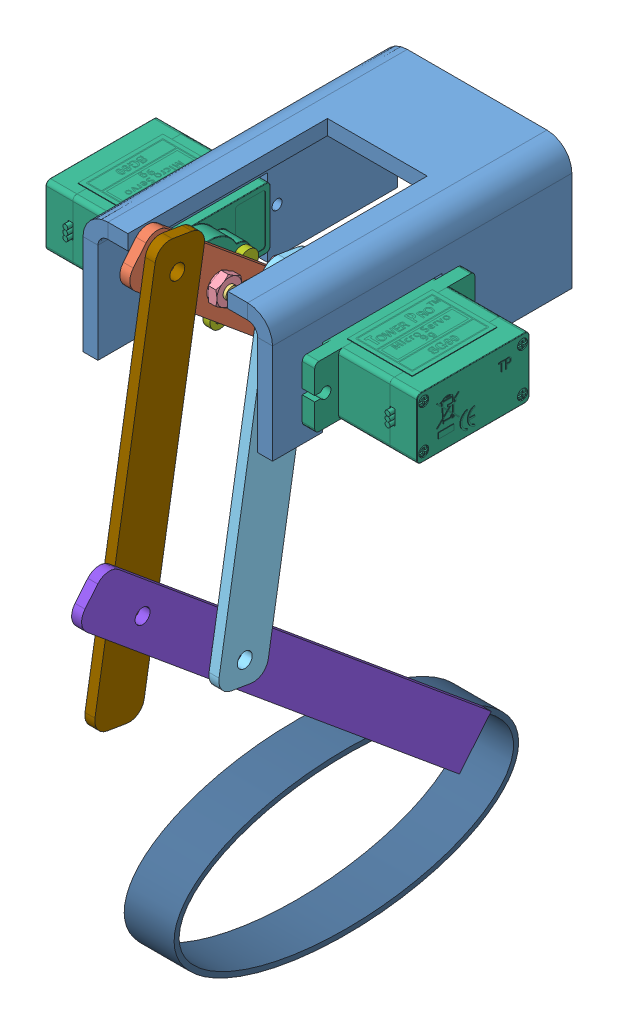
SolidWorks assembly 4 bar solution assembly, configuration Default. Lengths in mm.
Overall size (74.6 140.44 90.84).
18 component instances, 10 part files, 59 mates.
Components (placement in the parent):
- casing for the 4 bar linkage-1: casing for the 4 bar linkage [Default] at (-5.3742 30.1241 -30.819) size (38 25 60)
- arm for servo1-1: arm for servo1 [Default] at (-14.4242 18.8349 7.0956) x (0 -0.638517 -0.769608) z (0 -0.769608 0.638517) size (40 2 10)
- pan head cross recess screw_bsi-2: pan head cross recess screw_bsi [BS EN ISO 7045 - M2.5 x 6 - Z - 6N] at (-17.9242 18.3433 6.5031) x (1 0 0) z (0 -0.535382 -0.84461) size (8.05 5 5)
- pan head cross recess screw_bsi-3: pan head cross recess screw_bsi [BS EN ISO 7045 - M2.5 x 6 - Z - 6N] at (-17.9242 10.1064 -3.4249) x (1 0 0) z (0 -0.826379 -0.563115) size (8.05 5 5)
- hex nut style 1 gradeab_bsi-5: hex nut style 1 gradeab_bsi [BS EN 24032 - M2.5 - W - N] at (-10.4242 10.1064 -3.4249) x (0 -0.306449 -0.951887) z (1 0 0) size (5 5.77 2)
- hex nut style 1 gradeab_bsi-6: hex nut style 1 gradeab_bsi [BS EN 24032 - M2.5 - W - N] at (-10.4242 18.3433 6.5031) x (0 0 -1) z (1 0 0) size (5 5.77 2)
- arm for servo2-1: arm for servo2 [Default] at (-3.3242 -9.8625 5.5192) x (0 0.986622 -0.163025) z (0 0.163025 0.986622) size (70 2 10)
- pan head cross recess screw_bsi-4: pan head cross recess screw_bsi [BS EN ISO 7045 - M2.5 x 6 - Z - 6N] at (0.1758 20.5885 0.4876) x (-1 0 0) z (0 -0.368719 0.929541) size (8.05 5 5)
- pan head cross recess screw_bsi-5: pan head cross recess screw_bsi [BS EN ISO 7045 - M2.5 x 6 - Z - 6N] at (0.1758 7.8611 2.5906) x (-1 0 0) z (0 -0.591563 0.806259) size (8.05 5 5)
- hex nut style 1 gradeab_bsi-8: hex nut style 1 gradeab_bsi [BS EN 24032 - M2.5 - W - N] at (-7.3242 20.5885 0.4876) x (0 -0.76274 -0.646705) z (-1 0 0) size (5 5.77 2)
- hex nut style 1 gradeab_bsi-10: hex nut style 1 gradeab_bsi [BS EN 24032 - M2.5 - W - N] at (-7.3242 7.8611 2.5906) x (0 -0.76274 -0.646705) z (-1 0 0) size (5 5.77 2)
- SG90 - Micro Servo 9g - Tower Pro.1-1: SG90 - Micro Servo 9g - Tower Pro.1 [Peça] at (17.7758 14.2248 -3.6109) x (0 0 -1) z (0 1 0) size (32.1 29.95 12.4)
- SG90 - Micro Servo 9g - Tower Pro.4-1: SG90 - Micro Servo 9g - Tower Pro.4 [Peça] at (-3.3242 14.2248 1.5391) x (0 0.163025 0.986622) z (0 -0.986622 0.163025) size (13 3.8 16.7)
- SG90 - Micro Servo 9g - Tower Pro.1-2: SG90 - Micro Servo 9g - Tower Pro.1 [Peça] at (-35.5242 14.2248 -3.6109) x (0 0 -1) z (0 -1 0) size (32.1 29.95 12.4)
- SG90 - Micro Servo 9g - Tower Pro.4-2: SG90 - Micro Servo 9g - Tower Pro.4 [Peça] at (-14.4242 14.2248 1.5391) x (0 -0.769608 0.638517) z (0 0.638517 0.769608) size (13 3.8 16.7)
- arm for servo3-1: arm for servo3 [Default] at (-10.4242 -50.6831 -2.3235) x (0 0.638517 0.769608) z (0 0.769608 -0.638517) size (100 2 10)
- arm for servo4-1: arm for servo4 [Default] at (-10.4242 -6.55 22.4741) x (0 0.986622 -0.163025) z (0 0.163025 0.986622) size (80 2 10)
- path-1: path [Default] at (-10.4242 -88.8646 -16.9534) x (0 0 1) z (-1 0 0) size (69.07 32.24 10)
Mates (geometry in assembly coordinates):
- Coincident3: coincident: plane of casing for the 4 bar linkage-1 through (-27.8742 30.1241 -30.819) normal (-1 0 0); plane of ? through (-27.8742 19.4748 -34.3465) normal (1 0 0)
- Concentric1: concentric: circle of casing for the 4 bar linkage-1; circle of ?
- Coincident5: coincident: plane of casing for the 4 bar linkage-1 through (10.1258 30.1241 -30.819) normal (1 0 0); plane of ? through (10.1258 8.9748 -34.3465) normal (-1 0 0)
- Concentric4: concentric: circle of casing for the 4 bar linkage-1; circle of ?
- Concentric5: concentric: circle of casing for the 4 bar linkage-1; circle of ?
- Concentric6: concentric: circle of casing for the 4 bar linkage-1; circle of ?
- Concentric9: concentric: cylinder of ? through (-14.4242 16.4911 -18.2578) axis (1 0 0) radius 1.25; cylinder of pan head cross recess screw_bsi-2 through (-43.3242 16.4911 -18.2578) axis (-1 0 0) radius 2.5
- Coincident7: coincident: plane of ? through (-15.8242 14.2248 -24.2965) normal (-1 0 0); plane of pan head cross recess screw_bsi-2 through (-15.8242 16.0183 -17.1006) normal (1 0 0)
- Concentric10: concentric: cylinder of ? through (22.4036 20.7247 -24.2548) axis (1 0 0) radius 1.25; cylinder of pan head cross recess screw_bsi-3 through (-40.5964 20.7247 -24.2548) axis (-1 0 0) radius 2.5
- Coincident8: coincident: plane of ? through (-13.0964 20.2474 -23.0996) normal (-1 0 0); plane of pan head cross recess screw_bsi-3 through (-13.0964 21.9747 -24.2548) normal (1 0 0)
- Concentric11: concentric: cylinder of ? through (-14.4242 11.9585 -30.3352) axis (1 0 0) radius 1.25; cylinder of pan head cross recess screw_bsi-3 through (-43.3242 11.9585 -30.3352) axis (-1 0 0) radius 1.25
- Concentric16: concentric: cylinder of arm for servo1-1 through (-15.4242 7.7753 1.6192) axis (1 0 0) radius 1.3; cylinder of pan head cross recess screw_bsi-3 through (-43.3242 7.7753 1.6192) axis (-1 0 0) radius 1.25
- Concentric19: concentric: cylinder of arm for servo1-1 through (-15.4242 20.6743 1.459) axis (1 0 0) radius 1.3; cylinder of pan head cross recess screw_bsi-2 through (-43.3242 20.6743 1.459) axis (-1 0 0) radius 1.25
- Concentric20: concentric: cylinder of pan head cross recess screw_bsi-2 through (-40.8242 7.7748 -24.2965) axis (-1 0 0) radius 1.25; cylinder of ? through (19.4695 7.7748 -24.2965) axis (-1 0 0) radius 1.25
- Concentric21: concentric: cylinder of pan head cross recess screw_bsi-3 through (-40.8242 20.6748 -24.2965) axis (-1 0 0) radius 1.25; cylinder of ? through (19.1734 20.6748 -24.2965) axis (-1 0 0) radius 1.25
- Coincident91: coincident: plane of ? through (-15.8242 14.2248 -24.2965) normal (-1 0 0); plane of pan head cross recess screw_bsi-3 through (-15.8242 12.1731 -29.1038) normal (1 0 0)
- Coincident101: coincident: plane of ? through (-14.4242 14.2248 -24.2965) normal (1 0 0); plane of arm for servo1-1 through (-14.4242 23.4712 0.3412) normal (-1 0 0)
- Concentric23: concentric: cylinder of arm for servo1-1 through (-11.9242 7.7748 -24.2965) axis (1 0 0) radius 1.3; cylinder of ? through (-28.3617 7.7748 -24.2965) axis (1 0 0) radius 1.25
- Coincident11: coincident: plane of pan head cross recess screw_bsi-2 through (-5.3242 7.302 -23.1394) normal (1 0 0); plane of ? through (-5.3242 6.7113 -26.9802) normal (-1 0 0)
- Concentric24: concentric: cylinder of pan head cross recess screw_bsi-3 through (-43.3242 7.7753 1.6192) axis (-1 0 0) radius 1.25; cylinder of hex nut style 1 gradeab_bsi-5 through (-35.4617 7.7753 1.6192) axis (1 0 0) radius 1.25
- Coincident12: coincident: plane of arm for servo1-1 through (-12.4242 21.4442 1.4494) normal (1 0 0); plane of hex nut style 1 gradeab_bsi-5 through (-12.4242 10.5232 0.7346) normal (-1 0 0)
- Concentric251: concentric: cylinder of arm for servo1-1 through (-15.4242 20.6743 1.459) axis (1 0 0) radius 1.3; cylinder of hex nut style 1 gradeab_bsi-6 through (-35.4617 20.6743 1.459) axis (1 0 0) radius 1.25
- Coincident151: coincident: plane of arm for servo1-1 through (-12.4242 21.4442 1.4494) normal (1 0 0); plane of hex nut style 1 gradeab_bsi-6 through (-12.4242 23.5611 1.459) normal (-1 0 0)
- Concentric271: concentric: cylinder of ? through (-3.3242 16.4911 -30.3352) axis (-1 0 0) radius 1.25; cylinder of pan head cross recess screw_bsi-5 through (25.5758 16.4911 -30.3352) axis (1 0 0) radius 1.25
- Coincident171: coincident: plane of ? through (-1.9242 14.2248 -24.2965) normal (1 0 0); plane of pan head cross recess screw_bsi-5 through (-1.9242 15.435 -31.0038) normal (-1 0 0)
- Concentric281: concentric: cylinder of arm for servo2-1 through (-2.3242 8.0743 -0.4033) axis (-1 0 0) radius 1.3; cylinder of pan head cross recess screw_bsi-5 through (25.5758 8.0743 -0.4033) axis (1 0 0) radius 1.25
- Concentric301: concentric: cylinder of ? through (-3.3242 11.9585 -18.2578) axis (-1 0 0) radius 1.25; cylinder of pan head cross recess screw_bsi-4 through (25.6839 11.9585 -18.2578) axis (1 0 0) radius 1.25
- Concentric341: concentric: cylinder of arm for servo2-1 through (-6.3036 19.9092 -22.2965) axis (1 0 0) radius 3; cylinder of ? through (-30.2948 21.3681 -19.6751) axis (1 0 0) radius 1.25
- Coincident201: coincident: plane of arm for servo2-1 through (-6.3036 -12.0908 -24.2965) normal (-1 0 0); plane of ? through (-7.2573 24.193 -20.2695) normal (-1 0 0)
- Concentric351: concentric: cylinder of arm for servo2-1 through (-2.3242 20.3754 3.4816) axis (-1 0 0) radius 1.3; cylinder of hex nut style 1 gradeab_bsi-8 through (17.7133 20.3754 3.4816) axis (-1 0 0) radius 1.25
- Coincident211: coincident: plane of arm for servo2-1 through (-5.3242 -9.0557 -5.8132) normal (-1 0 0); plane of hex nut style 1 gradeab_bsi-8 through (-5.3242 18.5085 5.6834) normal (1 0 0)
- Concentric361: concentric: cylinder of arm for servo2-1 through (-2.3242 8.0743 -0.4033) axis (-1 0 0) radius 1.3; cylinder of hex nut style 1 gradeab_bsi-10 through (17.7133 8.0743 -0.4033) axis (-1 0 0) radius 1.25
- Coincident231: coincident: plane of arm for servo2-1 through (-5.3242 -9.0557 -5.8132) normal (-1 0 0); plane of hex nut style 1 gradeab_bsi-10 through (-5.3242 6.2074 1.7985) normal (1 0 0)
- Coincident24: coincident: plane of casing for the 4 bar linkage-1 through (10.1258 30.1241 -30.819) normal (1 0 0); plane of SG90 - Micro Servo 9g - Tower Pro.1-1 through (10.1258 19.4748 11.5891) normal (-1 0 0)
- Concentric37: concentric: circle of casing for the 4 bar linkage-1; circle of SG90 - Micro Servo 9g - Tower Pro.1-1
- Concentric38: concentric: circle of casing for the 4 bar linkage-1; circle of SG90 - Micro Servo 9g - Tower Pro.1-1
- Concentric39: concentric: circle of SG90 - Micro Servo 9g - Tower Pro.1-1; circle of SG90 - Micro Servo 9g - Tower Pro.4-1
- Coincident25: coincident: plane of SG90 - Micro Servo 9g - Tower Pro.1-1 through (-1.5242 14.2248 1.5391) normal (-1 0 0); plane of SG90 - Micro Servo 9g - Tower Pro.4-1 through (-1.5242 14.2248 1.5391) normal (1 0 0)
- Concentric40: concentric: cylinder of pan head cross recess screw_bsi-4 through (25.5758 20.3754 3.4816) axis (1 0 0) radius 1.25; cylinder of SG90 - Micro Servo 9g - Tower Pro.4-1 through (-3.3242 20.3754 3.4816) axis (-1 0 0) radius 1.25
- Coincident26: coincident: plane of pan head cross recess screw_bsi-4 through (-1.9242 19.2135 3.0207) normal (-1 0 0); plane of SG90 - Micro Servo 9g - Tower Pro.4-1 through (-1.9242 14.2248 1.5391) normal (1 0 0)
- Coincident27: coincident: plane of pan head cross recess screw_bsi-5 through (-1.9242 7.0664 -1.1428) normal (-1 0 0); plane of SG90 - Micro Servo 9g - Tower Pro.4-1 through (-1.9242 14.2248 1.5391) normal (1 0 0)
- Concentric41: concentric: cylinder of pan head cross recess screw_bsi-5 through (25.5758 8.0743 -0.4033) axis (1 0 0) radius 1.25; cylinder of SG90 - Micro Servo 9g - Tower Pro.4-1 through (-3.3242 8.0743 -0.4033) axis (-1 0 0) radius 1.25
- Coincident28: coincident: plane of arm for servo2-1 through (-3.3242 -9.0557 -5.8132) normal (1 0 0); plane of SG90 - Micro Servo 9g - Tower Pro.4-1 through (-3.3242 14.2248 1.5391) normal (-1 0 0)
- Concentric42: concentric: cylinder of arm for servo2-1 through (-2.3242 20.3754 3.4816) axis (-1 0 0) radius 1.3; cylinder of pan head cross recess screw_bsi-4 through (25.5758 20.3754 3.4816) axis (1 0 0) radius 1.25
- Coincident29: coincident: plane of casing for the 4 bar linkage-1 through (-27.8742 30.1241 -30.819) normal (-1 0 0); plane of SG90 - Micro Servo 9g - Tower Pro.1-2 through (-27.8742 8.9748 11.5891) normal (1 0 0)
- Concentric43: concentric: circle of casing for the 4 bar linkage-1; circle of SG90 - Micro Servo 9g - Tower Pro.1-2
- Concentric44: concentric: circle of casing for the 4 bar linkage-1; circle of SG90 - Micro Servo 9g - Tower Pro.1-2
- Concentric45: concentric: circle of SG90 - Micro Servo 9g - Tower Pro.1-2; circle of SG90 - Micro Servo 9g - Tower Pro.4-2
- Coincident30: coincident: plane of SG90 - Micro Servo 9g - Tower Pro.1-2 through (-16.2242 14.2248 1.5391) normal (1 0 0); plane of SG90 - Micro Servo 9g - Tower Pro.4-2 through (-16.2242 14.2248 1.5391) normal (-1 0 0)
- Coincident31: coincident: plane of arm for servo1-1 through (-14.4242 21.4442 1.4494) normal (-1 0 0); plane of SG90 - Micro Servo 9g - Tower Pro.4-2 through (-14.4242 14.2248 1.5391) normal (1 0 0)
- Concentric46: concentric: cylinder of pan head cross recess screw_bsi-3 through (-43.3242 7.7753 1.6192) axis (-1 0 0) radius 1.25; cylinder of SG90 - Micro Servo 9g - Tower Pro.4-2 through (-14.4242 7.7753 1.6192) axis (1 0 0) radius 1.25
- Concentric47: concentric: cylinder of pan head cross recess screw_bsi-2 through (-43.3242 20.6743 1.459) axis (-1 0 0) radius 1.25; cylinder of SG90 - Micro Servo 9g - Tower Pro.4-2 through (-14.4242 20.6743 1.459) axis (1 0 0) radius 1.25
- Coincident32: coincident: plane of pan head cross recess screw_bsi-3 through (-15.8242 7.0713 2.6521) normal (1 0 0); plane of SG90 - Micro Servo 9g - Tower Pro.4-2 through (-15.8242 14.2248 1.5391) normal (-1 0 0)
- Coincident33: coincident: plane of pan head cross recess screw_bsi-2 through (-15.8242 19.6186 2.1282) normal (1 0 0); plane of SG90 - Micro Servo 9g - Tower Pro.4-2 through (-15.8242 14.2248 1.5391) normal (-1 0 0)
- Coincident36: coincident: circle of arm for servo4-1; circle of arm for servo1-1
- Concentric50: concentric: cylinder of arm for servo3-1 through (-8.4242 -18.2234 -15.2728) axis (1 0 0) radius 1.5; cylinder of arm for servo4-1 through (-10.4242 -18.2234 -15.2728) axis (1 0 0) radius 1.5
- Concentric51: concentric: cylinder of arm for servo3-1 through (-8.4242 -38.2218 -15.0244) axis (1 0 0) radius 1.5; cylinder of arm for servo2-1 through (-5.3242 -38.2218 -15.0244) axis (-1 0 0) radius 1.5
- Coincident232: coincident: plane of arm for servo3-1 through (-10.4242 -54.89 -14.8173) normal (-1 0 0); plane of arm for servo4-1 through (-10.4242 1.8017 -8.9486) normal (1 0 0)
- PathMate3: path: point of arm for servo3-1; curve of path-1
